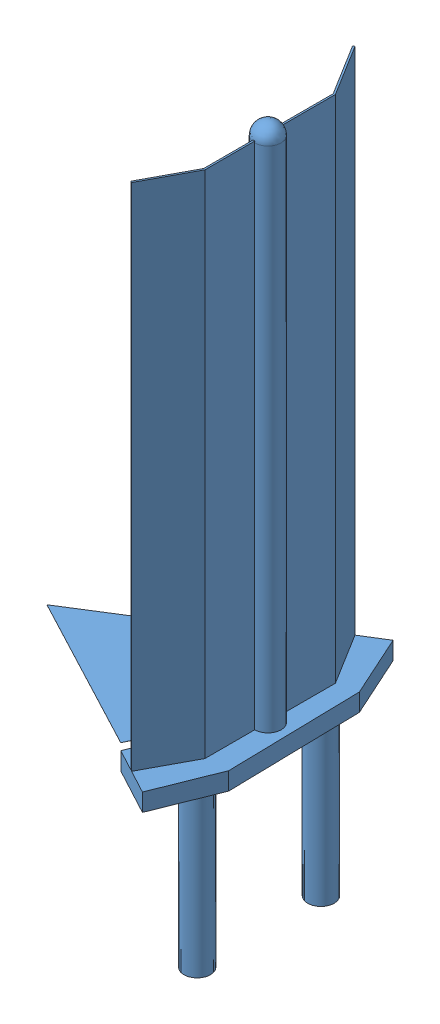
SolidWorks assembly Assem1, configuration Default. Lengths in mm.
Overall size (1376.61 4000 1452.28).
2 component instances, 2 part files, 1 mates.
Components (placement in the parent):
- TrampolineMat-2: TrampolineMat [Default] at (20357.6625 -5441.3233 17993.2456) size (1376.61 4000 1452.28)
- lecture4_springwithhook_21010264-3: lecture4_springwithhook_21010264 [Default] at (21390.7926 -5541.8083 17954.8384) size (114.8 37.29 37.22)
Mates (geometry in assembly coordinates):
- Lock2: lock: unknown of TrampolineMat-2; unknown of lecture4_springwithhook_21010264-3
